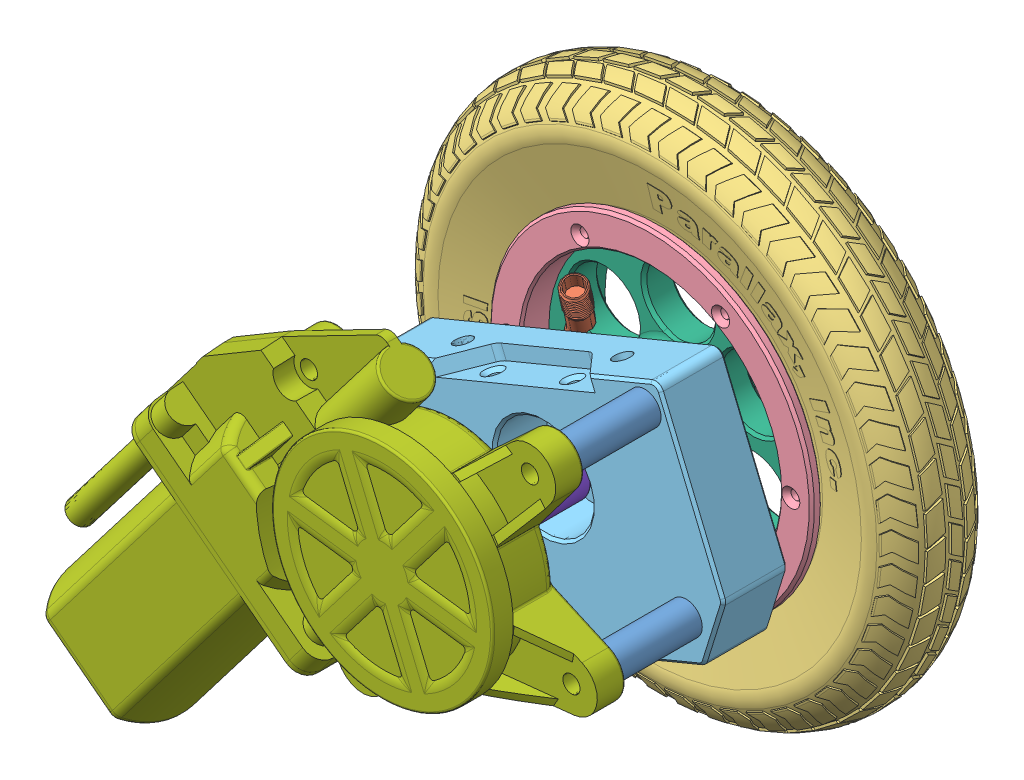
SolidWorks assembly motor_assembly, configuration Défaut. Lengths in mm.
Overall size (203.62 165.07 107.73).
11 component instances, 8 part files, 19 mates.
Components (placement in the parent):
- 28962-28963-8-IDx1-Al-Spacer-1: 28962-28963-8-IDx1-Al-Spacer [92510A629] at (74.875 4.2471 122.0159) size (9.53 9.53 25.4)
- 28962-28963-Inner-Tube-1: 28962-28963-Inner-Tube [Default] at (119.3259 2.1405 65.4464) size (149.61 149.61 26.31)
- 28962-28963-Rubber-Tire-1: 28962-28963-Rubber-Tire [Default] at (119.3259 -58.8798 64.1623) size (154.71 154.78 28.25)
- 28962-28963-Wheel-Rim-Ring-Section-1: 28962-28963-Wheel-Rim-Ring-Section [Default] at (119.3259 2.1405 65.1199) size (95.25 95.25 8.25)
- 28962-Motor-Bearing-Block-2-Aluminum-1: 28962-Motor-Bearing-Block-2-Aluminum [Default] at (119.3259 2.1405 109.3159) x (-0.923728 -0.383049 0) z (0.383049 -0.923728 0) size (93.98 19.31 66.04)
- 28962-Wheel-Main-Rim-Section-AL-1: 28962-Wheel-Main-Rim-Section-AL [Default] at (119.3259 2.1405 65.1199) size (95.25 95.25 24.13)
- 750-90006-Motor12VDC-1: 750-90006-Motor12VDC [Default] at (119.2558 1.9713 156.7504) x (-0.923728 -0.383049 0) z (0.383049 -0.923728 0) size (165.94 33.59 93.96)
- Drive Axle-34031-1: Drive Axle-34031 [Default] at (119.3259 2.1405 131.7949) x (-0.923728 -0.383049 0) z (0.383049 -0.923728 0) size (21.59 66.67 21.59)
- 28962-28963-8-IDx1-Al-Spacer-2: 28962-28963-8-IDx1-Al-Spacer [92510A629] at (149.2417 35.0854 122.0159) size (9.53 9.53 25.4)
- 28962-28963-8-IDx1-Al-Spacer-3: 28962-28963-8-IDx1-Al-Spacer [92510A629] at (99.8893 -37.8912 122.0159) size (9.53 9.53 25.4)
- 28962-28963-8-IDx1-Al-Spacer-4: 28962-28963-8-IDx1-Al-Spacer [92510A629] at (161.3878 -12.3892 122.0159) size (9.53 9.53 25.4)
Mates (geometry in assembly coordinates):
- Coaxiale1: concentric: cylinder of 28962-28963-Inner-Tube-1 through (119.3259 2.1405 65.4464) axis (0 0 -1) radius 47.8634; cylinder of 28962-Wheel-Main-Rim-Section-AL-1 through (119.3259 2.1405 119.1267) axis (0 0 -1) radius 43.815
- Coaxiale2: concentric: circle of 28962-28963-Rubber-Tire-1; circle of 28962-Wheel-Main-Rim-Section-AL-1
- Coïncidente2: coincident: plane of 28962-28963-Wheel-Rim-Ring-Section-1 through (119.3259 2.1405 69.5649) normal (0 0 -1); plane of 28962-Wheel-Main-Rim-Section-AL-1 through (81.2259 2.1405 69.5649) normal (0 0 1)
- Coaxiale3: concentric: circle of 28962-28963-Wheel-Rim-Ring-Section-1; circle of 28962-Wheel-Main-Rim-Section-AL-1
- Coaxiale4: concentric: circle of 750-90006-Motor12VDC-1; circle of Drive Axle-34031-1
- Parallèle2: parallel: plane of 750-90006-Motor12VDC-1 through (116.5778 -4.5012 124.1749) normal (0.383049 -0.923728 0); plane of Drive Axle-34031-1 through (117.7208 -3.942 124.1749) normal (-0.383049 0.923728 0)
- Coïncidente5: coincident: plane of 750-90006-Motor12VDC-1 through (119.2558 1.9713 124.1749) normal (0 0 -1); plane of Drive Axle-34031-1 through (117.2645 -2.8416 124.1749) normal (0 0 1)
- Coaxiale5: concentric: cylinder of 28962-Wheel-Main-Rim-Section-AL-1 through (119.3259 2.1405 65.1199) axis (0 0 1) radius 6.35; cylinder of Drive Axle-34031-1 through (119.3259 2.1405 65.1199) axis (0 0 1) radius 6.3373
- Coaxiale6: concentric: cylinder of 28962-Motor-Bearing-Block-2-Aluminum-1 through (119.3259 2.1405 90.2659) axis (0 0 1) radius 8.89; cylinder of Drive Axle-34031-1 through (119.3259 2.1405 65.1199) axis (0 0 1) radius 6.3373
- Coaxiale7: concentric: cylinder of 28962-28963-8-IDx1-Al-Spacer-1 through (74.875 4.2471 134.7159) axis (0 0 -1) radius 2.1082; cylinder of 28962-Motor-Bearing-Block-2-Aluminum-1 through (74.875 4.2471 90.2659) axis (0 0 -1) radius 3
- Coaxiale8: concentric: cylinder of 28962-Motor-Bearing-Block-2-Aluminum-1 through (149.2417 35.0854 90.2659) axis (0 0 -1) radius 3; cylinder of 28962-28963-8-IDx1-Al-Spacer-2 through (149.2417 35.0854 134.7159) axis (0 0 -1) radius 2.1082
- Coaxiale9: concentric: cylinder of 28962-Motor-Bearing-Block-2-Aluminum-1 through (99.8893 -37.8912 90.2659) axis (0 0 -1) radius 3; cylinder of 28962-28963-8-IDx1-Al-Spacer-3 through (99.8893 -37.8912 134.7159) axis (0 0 -1) radius 2.1082
- Coaxiale10: concentric: cylinder of 28962-Motor-Bearing-Block-2-Aluminum-1 through (161.3878 -12.3892 90.2659) axis (0 0 -1) radius 3; cylinder of 28962-28963-8-IDx1-Al-Spacer-4 through (161.3878 -12.3892 134.7159) axis (0 0 -1) radius 2.1082
- Coïncidente6: coincident: plane of 28962-Motor-Bearing-Block-2-Aluminum-1 through (119.3259 2.1405 109.3159) normal (0 0 1); plane of 28962-28963-8-IDx1-Al-Spacer-2 through (149.2417 35.0854 109.3159) normal (0 0 -1)
- Coïncidente7: coincident: plane of 28962-Motor-Bearing-Block-2-Aluminum-1 through (119.3259 2.1405 109.3159) normal (0 0 1); plane of 28962-28963-8-IDx1-Al-Spacer-4 through (161.3878 -12.3892 109.3159) normal (0 0 -1)
- Coïncidente8: coincident: plane of 28962-28963-8-IDx1-Al-Spacer-1 through (74.875 4.2471 109.3159) normal (0 0 -1); plane of 28962-Motor-Bearing-Block-2-Aluminum-1 through (119.3259 2.1405 109.3159) normal (0 0 1)
- Coïncidente9: coincident: plane of 28962-Motor-Bearing-Block-2-Aluminum-1 through (119.3259 2.1405 109.3159) normal (0 0 1); plane of 28962-28963-8-IDx1-Al-Spacer-3 through (99.8893 -37.8912 109.3159) normal (0 0 -1)
- Coïncidente10: coincident: plane of 750-90006-Motor12VDC-1 through (149.0506 34.9494 134.7159) normal (0 0 -1); plane of 28962-28963-8-IDx1-Al-Spacer-4 through (161.3878 -12.3892 134.7159) normal (0 0 1)
- Coïncidente11: coincident: plane of 28962-Wheel-Main-Rim-Section-AL-1 through (119.3259 2.1405 65.1199) normal (0 0 1); plane of Drive Axle-34031-1 through (119.3259 2.1405 65.1199) normal (0 0 -1)
